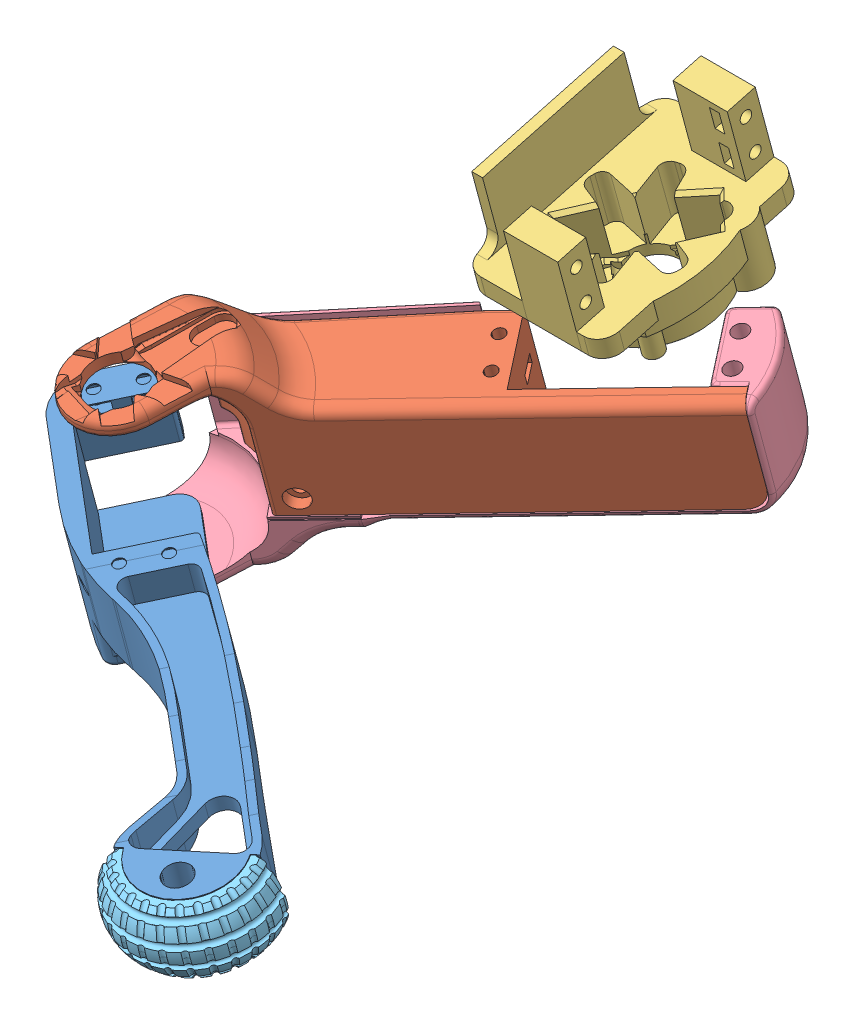
SolidWorks assembly Left Arm, configuration Default. Lengths in mm.
Overall size (144.09 143.1 205.53).
5 component instances, 5 part files, 0 mates.
Components (placement in the parent):
- Left_Wrist-1: Left_Wrist [Default] at (208.18 556.7001 -69.0557) x (0.766044 -0.166366 0.620885) z (-0.642788 -0.198267 0.739942) size (150.01 36.9 30.01)
- Left_MidLimb-1: Left_MidLimb [Default] at (818.6858 196.1975 -412.3318) x (-0.573576 0.212012 -0.79124) z (-0.819152 -0.148453 0.554032) size (40.2 40.42 137.43)
- Left_Hind_Limb-1: Left_Hind_Limb [Default] at (269.686 62.3829 30.3404) x (0 -0.965926 -0.258819) z (0 0.258819 -0.965926) size (37.51 46 56.55)
- Left_MidLimb_Cover-1: Left_MidLimb_Cover [Default] at (1075.7599 185.3339 -217.1444) x (-0.573576 0.212012 -0.79124) z (-0.819152 -0.148453 0.554032) size (43.12 46.4 143.61)
- Foot-1: Foot [Default] at (334.478 189.9471 78.7023) x (0.864275 0.130191 -0.48588) z (-0.50302 0.223691 -0.834825) size (39.57 20.99 19.53)
